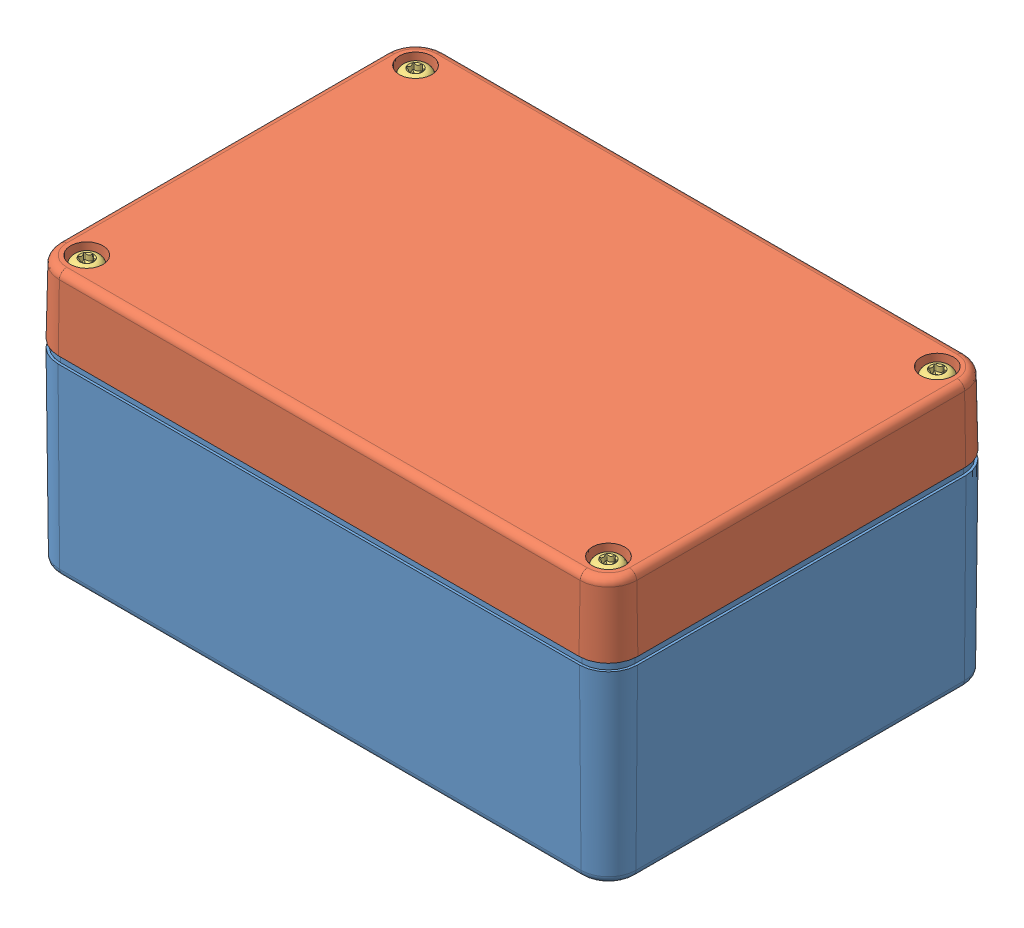
SolidWorks assembly Assem338, configuration Default. Lengths in mm.
Overall size (119.99 54.99 80.06).
16 component instances, 6 part files, 0 mates.
Components (placement in the parent):
- serpac_tx2_enclosure-1: serpac_tx2_enclosure [Default] at (45.3124 80.906 87.8997) size (119.99 54.99 80.06)
  - RB53X16Y_RevB(Default)-1: RB53X16Y_RevB(Default) [Default] at origin size (119.96 42.04 80.01)
  - RB53-X06Y_RevB-1: RB53-X06Y_RevB [Default] x (-1 0 0) z (0 0 1) size (119.99 14.99 80.06)
  - 6023_Pan_Head_screw_torx_head-4-40_Rev_B-2-1: 6023_Pan_Head_screw_torx_head-4-40_Rev_B-2 [Default] at (54.0004 -12.954 34.036) x (1 0 0) z (0 1 0) size (5.56 5.56 27.69)
  - 6023_Pan_Head_screw_torx_head-4-40_Rev_B-2-2: 6023_Pan_Head_screw_torx_head-4-40_Rev_B-2 [Default] at (-54.0004 -12.954 34.036) x (1 0 0) z (0 1 0) size (5.56 5.56 27.69)
  - 6023_Pan_Head_screw_torx_head-4-40_Rev_B-2-3: 6023_Pan_Head_screw_torx_head-4-40_Rev_B-2 [Default] at (54.0004 -12.954 -34.036) x (1 0 0) z (0 1 0) size (5.56 5.56 27.69)
  - 6023_Pan_Head_screw_torx_head-4-40_Rev_B-2-4: 6023_Pan_Head_screw_torx_head-4-40_Rev_B-2 [Default] at (-54.0004 -12.954 -34.036) x (1 0 0) z (0 1 0) size (5.56 5.56 27.69)
  - 6102_4-40_threaded insert-2-1: 6102_4-40_threaded insert-2 [Default] at (-54.0004 -6.096 -34.036) x (-0.837169 0 -0.546944) z (-0.546944 0 0.837169) size (5.82 5.08 5.82)
  - 6102_4-40_threaded insert-2-2: 6102_4-40_threaded insert-2 [Default] at (54.0004 -6.096 -34.036) x (-0.837169 0 -0.546944) z (-0.546944 0 0.837169) size (5.82 5.08 5.82)
  - 6102_4-40_threaded insert-2-3: 6102_4-40_threaded insert-2 [Default] at (-54.0004 -6.096 34.036) x (-0.837169 0 -0.546944) z (-0.546944 0 0.837169) size (5.82 5.08 5.82)
  - 6102_4-40_threaded insert-2-4: 6102_4-40_threaded insert-2 [Default] at (54.0004 -6.096 34.036) x (-0.837169 0 -0.546944) z (-0.546944 0 0.837169) size (5.82 5.08 5.82)
  - 6022 #10-16 HL Pan HD-2-1: 6022 #10-16 HL Pan HD-2 [Default] at (40.7416 -32.004 -29.0068) x (1 0 0) z (0 1 0) size (8.18 8.18 9.67)
  - 6022 #10-16 HL Pan HD-2-2: 6022 #10-16 HL Pan HD-2 [Default] at (-40.7416 -32.004 29.0068) x (1 0 0) z (0 1 0) size (8.18 8.18 9.67)
  - 6022 #10-16 HL Pan HD-2-3: 6022 #10-16 HL Pan HD-2 [Default] at (40.7416 -32.004 29.0068) x (1 0 0) z (0 1 0) size (8.18 8.18 9.67)
  - 6022 #10-16 HL Pan HD-2-4: 6022 #10-16 HL Pan HD-2 [Default] at (-40.7416 -32.004 -29.0068) x (1 0 0) z (0 1 0) size (8.18 8.18 9.67)
  - RB53 O Ring Rev A-1: RB53 O Ring Rev A [Default] at (0 1.4224 0) size (117.3 2.29 77.27)
